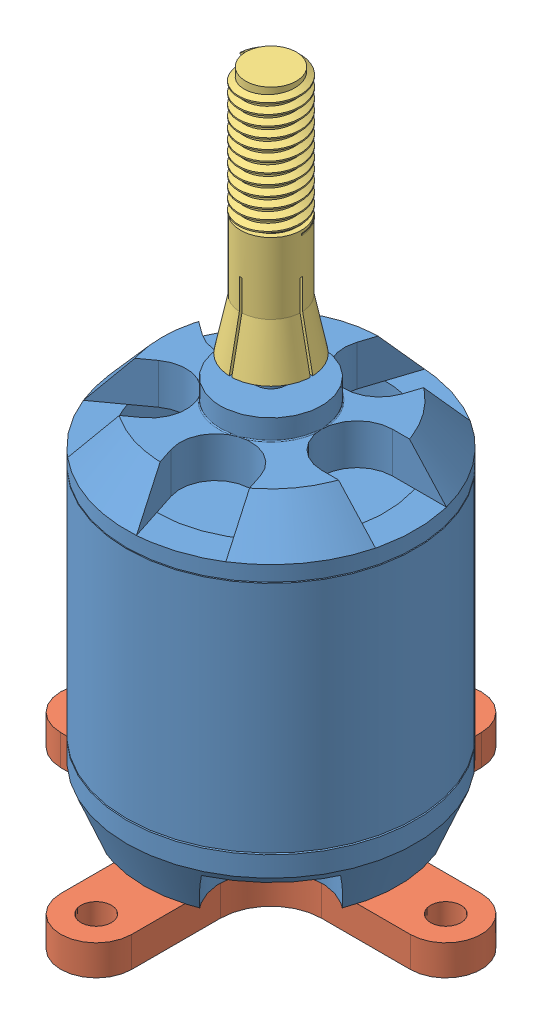
SolidWorks assembly BL2220-07, configuration Default. Lengths in mm.
Overall size (41.5 66.8 41.5).
3 component instances, 3 part files, 5 mates.
Components (placement in the parent):
- BL2220-07 Body-1: BL2220-07 Body [Default] at (-1.0176 4.7082 50.2596) size (28.5 52.3 28.5)
- BL2220-07 Mount-1: BL2220-07 Mount [Default] at (-1.0176 4.7082 50.2596) x (-1 0 0) z (0 0 1) size (41.5 3 41.5)
- BL2220-07 Stock-1: BL2220-07 Stock [Default] at (-1.0176 44.0082 50.2596) size (8 24.5 8)
Mates (geometry in assembly coordinates):
- Coincident1: coincident: plane of BL2220-07 Body-1 through (-1.0176 4.7082 50.2596) normal (0 -1 0); plane of BL2220-07 Mount-1 through (-1.0176 4.7082 33.0096) normal (0 1 0)
- Concentric1: concentric: circle of BL2220-07 Body-1; circle of BL2220-07 Mount-1
- Concentric2: concentric: circle of BL2220-07 Body-1; circle of BL2220-07 Mount-1
- Concentric3: concentric: cylinder of BL2220-07 Body-1 through (-1.0176 2.2082 50.2596) axis (0 1 0) radius 1.5; cylinder of BL2220-07 Stock-1 through (-1.0176 58.5082 50.2596) axis (0 -1 0) radius 1.55
- Distance1: distance = 2 mm: plane of BL2220-07 Stock-1 through (-1.0176 44.0082 50.2596) normal (0 -1 0); plane of BL2220-07 Body-1 through (-1.0176 42.0082 50.2596) normal (0 1 0)
